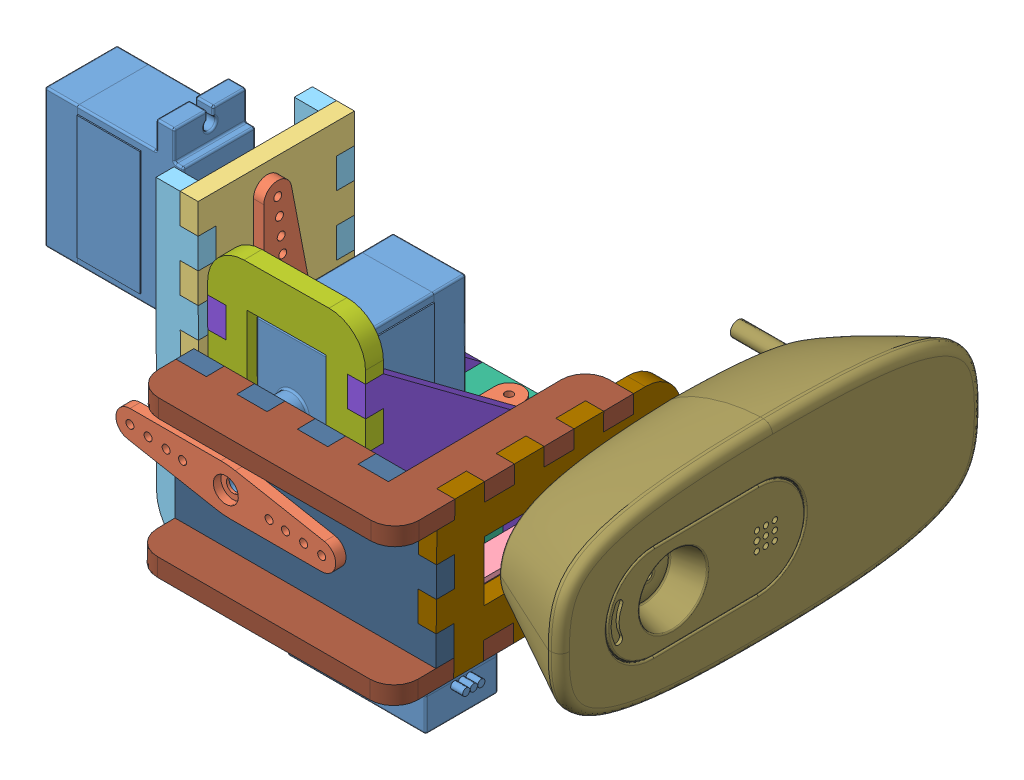
SolidWorks assembly gimbal, configuration Default. Lengths in mm.
Overall size (109.12 70.48 85.88).
25 component instances, 12 part files, 22 mates.
Components (placement in the parent):
- servo with horn-1: servo with horn [Default] at (0.4108 13.0639 -25.2845) x (0 -1 0) z (0 0 1) size (37.71 34.23 29.15) (flexible)
  - Servo-MG90S-1: Servo-MG90S [Default] at (1.5639 -0.4108 31.2845) size (32.2 32.5 12.4)
  - Micro Servo Horn Arm-1: Micro Servo Horn Arm [Default] at (6.8139 29.5492 31.2845) x (0.995434 0 -0.095456) z (0.095456 0 0.995434) size (36.39 4.27 7.53)
- servo with horn-3: servo with horn [Default] at (50.6861 -37.7861 -24.8604) x (1 0 0) z (0 -0.001724 0.999999) size (37.71 34.23 29.15) (flexible)
  - Servo-MG90S-1: Servo-MG90S [Default] at (1.5639 -0.4108 31.2845) size (32.2 32.5 12.4)
  - Micro Servo Horn Arm-1: Micro Servo Horn Arm [Default] at (6.8139 29.5492 31.2845) x (-0.103168 0 -0.994664) z (0.994664 0 -0.103168) size (36.39 4.27 7.53)
- roll-pan linkage plate-1: roll-pan linkage plate [Default] at (34.9529 22.7251 -33.0023) x (0 0.999999 0.001724) z (0 -0.001724 0.999999) size (53 45 26) (flexible)
  - roll-pan base plate-4: roll-pan base plate [Default] at (-16.4079 3.9529 39.0307) size (43 3 26)
  - roll-pan servo holder plate-6: roll-pan servo holder plate [Default] at (-37.9079 -16.5471 39.0307) x (0 -1 0) z (0 0 1) size (41 3 26)
  - roll-pan joiner plate-1: roll-pan joiner plate [Default] at (-25.4079 -9.0471 52.0307) x (1 0 0) z (0 1 0) size (53 3 37)
  - roll-pan joiner plate-2: roll-pan joiner plate [Default] at (-25.4079 -9.0471 29.0307) x (1 0 0) z (0 1 0) size (53 3 37)
- pan-tilt linkage plate-1: pan-tilt linkage plate [Default] at (45.6589 -20.1777 47.5775) x (-0.009475 0.001724 -0.999954) z (0.999955 0.000016 -0.009475) size (43 41 26) (flexible)
  - pan-tilt base plate-1: pan-tilt base plate [Default] at (41.009 12.856 12.2302) size (43 3 26)
  - pan-tilt servo holder plate-1: pan-tilt servo holder plate [Default] at (19.509 33.356 12.2302) x (0 1 0) z (0 0 1) size (41 3 26)
  - pan-tilt joiner plate-1: pan-tilt joiner plate [Default] at (41.009 29.356 23.7302) x (-1 0 0) z (0 -1 0) size (43 3 33)
  - pan-tilt joiner plate-2: pan-tilt joiner plate [Default] at (41.009 29.356 0.7302) x (-1 0 0) z (0 -1 0) size (43 3 33)
- servo with horn-4: servo with horn [Default] at (88.2728 14.0654 5.1326) x (0 -0.999999 -0.001724) z (-0.999955 -0.000016 0.009475) size (37.71 34.23 29.15) (flexible)
  - Servo-MG90S-1: Servo-MG90S [Default] at (1.5639 -0.4108 31.2845) size (32.2 32.5 12.4)
  - Micro Servo Horn Arm-1: Micro Servo Horn Arm [Default] at (6.8139 29.5492 31.2845) x (-0.102648 0 0.994718) z (-0.994718 0 -0.102648) size (36.39 4.27 7.53)
- servo-camera linkage plate-1: servo-camera linkage plate [Default] at (71.7288 -15.2944 -18.9937) x (-0.999915 0.008935 0.00949) z (0.008951 0.999959 0.001639) size (43 48 26)
  - camera holder plate-1: camera holder plate [Default] at (-16.3291 34.3206 22.4525) x (0 -1 0) z (0 0 1) size (41 3 26)
  - servo-camera base plate-1: servo-camera base plate [Default] at (5.1709 54.8206 22.4525) size (43 3 26)
  - servo-camera joiner plate-1: servo-camera joiner plate [Default] at (-2.8291 43.3206 35.4525) x (1 0 0) z (0 1 0) size (43 3 40)
  - servo-camera joiner plate-2: servo-camera joiner plate [Default] at (-2.8291 43.3206 12.4525) x (1 0 0) z (0 1 0) size (43 3 40)
- Logitech c270-1: Logitech c270 [Default] at (104.9067 5.3341 -1.9511) x (-0.009475 0.001724 -0.999954) z (0.999915 -0.008935 -0.00949) size (78.48 38.83 28.67)
Mates (geometry in assembly coordinates):
- Coincident4: coincident anti-aligned: plane of roll-pan linkage plate-1/roll-pan servo holder plate-6 through (63.5 13.5559 -0.4874) normal (-1 0 0); plane of servo with horn-3/Servo-MG90S-1 through (63.5 -15.2612 12.4629) normal (1 0 0)
- Coincident5: coincident anti-aligned: plane of servo with horn-3/Servo-MG90S-1 through (40.75 -19.7612 12.4552) normal (0 -0.001724 0.999999); plane of roll-pan linkage plate-1/roll-pan servo holder plate-6 through (63.5 13.5335 12.5126) normal (0 0.001724 -0.999999)
- Coincident6: coincident anti-aligned: plane of servo with horn-1/Servo-MG90S-1 through (18.5 23 0) normal (0 0 -1)
- Coincident7: coincident anti-aligned: plane of servo with horn-1/Servo-MG90S-1 through (0 11.5 6) normal (-1 0 0)
- Coincident8: coincident anti-aligned: plane of servo with horn-1/Servo-MG90S-1 through (18.5 0 12) normal (0 -1 0)
- Coincident10: coincident anti-aligned: plane of servo with horn-3/Servo-MG90S-1 through (52.25 -16.7508 6.4604) normal (0 0.999999 0.001724); plane of roll-pan linkage plate-1/roll-pan servo holder plate-6 through (51.5 -16.75 5.9604) normal (0 -0.999999 -0.001724)
- Concentric1: concentric anti-aligned: cylinder of servo with horn-1/Micro Servo Horn Arm-1 through (32.5 6.25 6) axis (-1 0 0) radius 3.3655; cylinder of roll-pan linkage plate-1/roll-pan base plate-4 through (18.1863 6.25 6) axis (1 0 0) radius 4
- Parallel1: parallel aligned: plane of servo with horn-1/Micro Servo Horn Arm-1 through (34.2272 35.1893 2.244) normal (0 0.001724 -0.999999); plane of roll-pan linkage plate-1/roll-pan base plate-4 through (29.5 -13.7276 -7.0345) normal (0 0.001724 -0.999999)
- Coincident12: coincident anti-aligned: plane of servo with horn-3/Micro Servo Horn Arm-1 through (60.4982 -5.8007 35.3849) normal (0 -0.999999 -0.001724); plane of pan-tilt linkage plate-1/pan-tilt base plate-1 through (57.5 -5.7508 6.4793) normal (0 0.999999 0.001724)
- Concentric2: concentric aligned: cylinder of servo with horn-3/Micro Servo Horn Arm-1 through (57.5 -5.7508 6.4793) axis (0 -0.999999 -0.001724) radius 3.3655; cylinder of pan-tilt linkage plate-1/pan-tilt base plate-1 through (57.5 5.5628 6.4988) axis (0 -0.999999 -0.001724) radius 4
- Parallel2: parallel aligned: plane of servo with horn-3/Micro Servo Horn Arm-1 through (53.9684 -4.0736 35.4498) normal (-0.999955 -0.000016 0.009475); plane of pan-tilt linkage plate-1/pan-tilt base plate-1 through (47.4057 0.0972 -3.4154) normal (-0.999955 -0.000016 0.009475)
- Coincident14: coincident anti-aligned: plane of pan-tilt linkage plate-1/pan-tilt servo holder plate-1 through (57.6895 13.2147 26.5111) normal (-0.009475 0.001724 -0.999954); plane of servo with horn-4/Servo-MG90S-1 through (57.1895 12.4647 26.5146) normal (0.009475 -0.001724 0.999954)
- Coincident15: coincident anti-aligned: plane of pan-tilt linkage plate-1/pan-tilt servo holder plate-1 through (51.4768 25.1623 56.8867) normal (0.999955 0.000016 -0.009475); plane of servo with horn-4/Servo-MG90S-1 through (51.1614 23.9697 23.5914) normal (-0.999955 -0.000016 0.009475)
- Coincident16: coincident anti-aligned: plane of pan-tilt linkage plate-1/pan-tilt servo holder plate-1 through (51.4768 1.1624 56.8453) normal (0 0.999999 0.001724); plane of servo with horn-4/Servo-MG90S-1 through (51.204 1.212 28.052) normal (0 -0.999999 -0.001724)
- Concentric3: concentric aligned: cylinder of servo with horn-4/Micro Servo Horn Arm-1 through (57.2937 7.1957 37.505) axis (-0.009475 0.001724 -0.999954) radius 3.3655; cylinder of servo-camera linkage plate-1/servo-camera base plate-1 through (57.4009 7.1762 48.8182) axis (-0.009475 0.001724 -0.999954) radius 4
- Coincident17: coincident anti-aligned: plane of servo with horn-4/Micro Servo Horn Arm-1 through (86.1997 4.2131 37.226) normal (-0.009475 0.001724 -0.999954); plane of servo-camera linkage plate-1/servo-camera base plate-1 through (67.2929 7.1063 37.4101) normal (0.009475 -0.001724 0.999954)
- Parallel3: parallel aligned: plane of servo with horn-4/Micro Servo Horn Arm-1 through (86.2063 3.1285 38.9513) normal (-0.008951 -0.999959 -0.001639); plane of servo-camera linkage plate-1/servo-camera base plate-1 through (67.2586 -2.9033 43.2244) normal (-0.008951 -0.999959 -0.001639)
- Coincident19: coincident anti-aligned: plane of servo-camera linkage plate-1/camera holder plate-1 through (90.0825 6.9387 15.1929) normal (0.999915 -0.008935 -0.00949); plane of Logitech c270-1 through (89.7847 13.7961 -22.6398) normal (-0.999915 0.008935 0.00949)
- Parallel4: parallel anti-aligned: plane of servo-camera linkage plate-1/servo-camera base plate-1 through (67.2929 7.1063 37.4101) normal (0.009475 -0.001724 0.999954); plane of Logitech c270-1 through (84.4056 2.0122 1.2375) normal (-0.009475 0.001724 -0.999954)
- Coincident21: coincident: plane of servo-camera linkage plate-1/camera holder plate-1 through (119.6347 1.6974 0.9032) normal (0.008951 0.999959 0.001639); line of Logitech c270-1 through (89.9051 1.9631 1.1853) axis (0.009475 -0.001724 0.999954)
- Coincident22: coincident anti-aligned: plane of servo-camera linkage plate-1/camera holder plate-1 through (119.6347 1.6974 0.9032) normal (0.009475 -0.001724 0.999954); plane of Logitech c270-1 through (84.4056 2.0122 1.2375) normal (-0.009475 0.001724 -0.999954)
- Coincident23: coincident anti-aligned: plane of servo with horn-1/Micro Servo Horn Arm-1 through (32.5 35.178 8.774) normal (-1 0 0); plane of roll-pan linkage plate-1/roll-pan base plate-4 through (32.5 6.25 6) normal (1 0 0)
